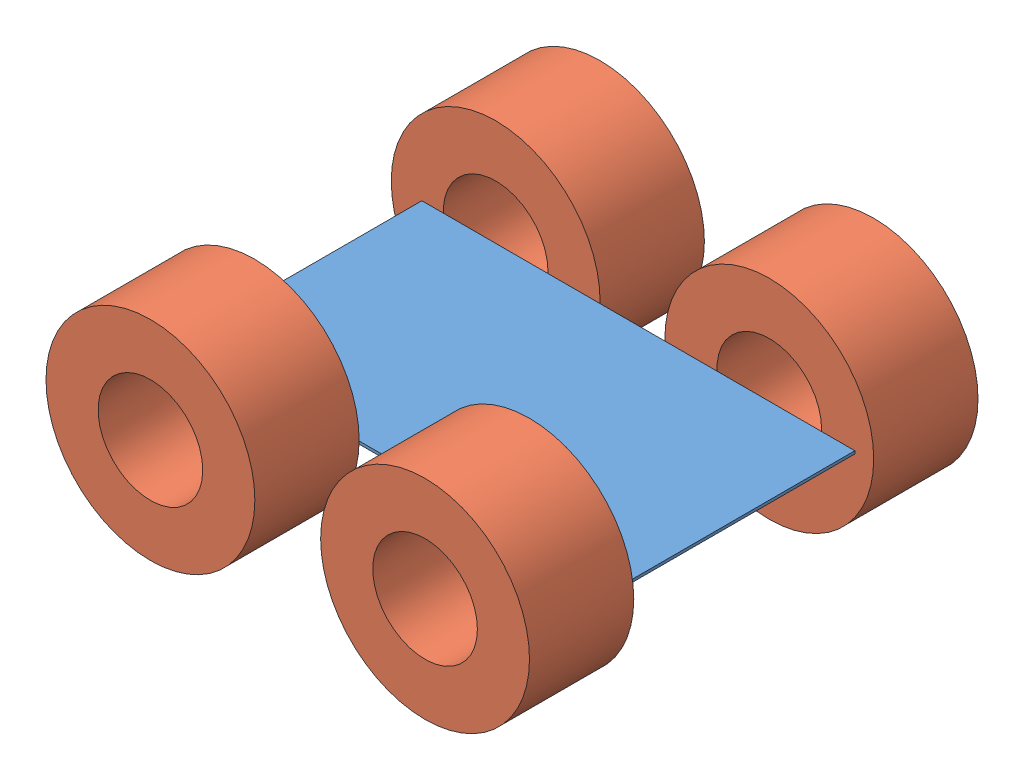
SolidWorks assembly robot, configuration Default. Lengths in mm.
Overall size (277.96 120.65 258.61).
5 component instances, 2 part files, 0 mates.
Components (placement in the parent):
- main-1: main [Default] at origin size (249.12 1.6 137.75)
- wheel-3: wheel [Default] at (-86.5554 2.0107 -134.2878) size (120.16 120.16 60)
- wheel-4: wheel [Default] at (71.0223 2.385 -134.1289) size (120.16 120.16 60)
- wheel-5: wheel [Default] at (-86.5957 2.2867 64.3179) size (120.16 120.16 60)
- wheel-6: wheel [Default] at (71.2034 1.8866 64.1051) size (120.16 120.16 60)
